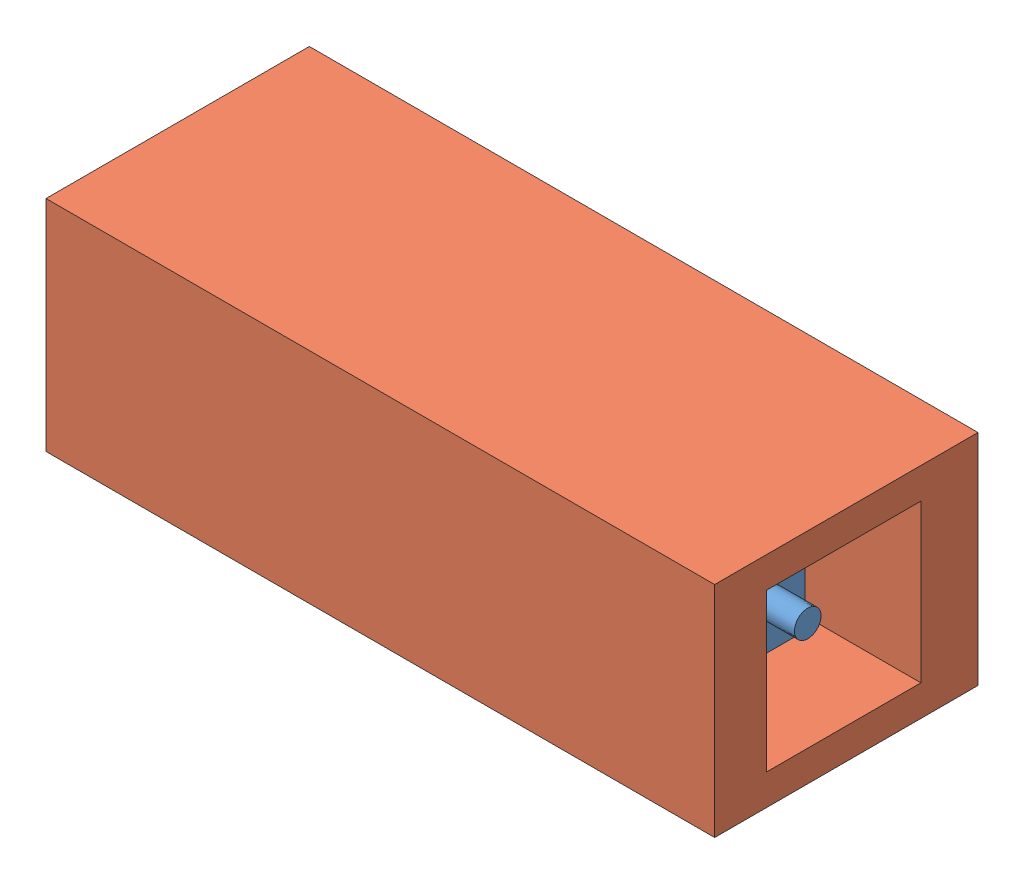
SolidWorks assembly v2, configuration Default. Lengths in mm.
Overall size (65 21.3 25.6).
3 component instances, 2 part files, 6 mates.
Components (placement in the parent):
- solenoid-1: solenoid [block] at (4.7939 41.8617 20.3007) size (30 15 15)
- solenoid-2: solenoid [stroke] at (-15.2061 41.8617 20.3007) x (1 0 0) z (0 0.379219 0.925307) size (57 6 6)
- Part3^v2-1: Part3^v2 [Default] at (4.7939 34.3617 20.3007) x (-1 0 0) z (0 -1 0) size (65 25.6 21.3) (virtual)
Mates (geometry in assembly coordinates):
- Concentric1: concentric aligned: cylinder of solenoid-1 through (4.7939 41.8617 20.3007) axis (-1 0 0) radius 3; cylinder of solenoid-2 through (-15.2061 41.8617 20.3007) axis (-1 0 0) radius 3
- LimitDistance2: limit distance = 20 mm aligned: plane of solenoid-2 through (-15.2061 41.8617 20.3007) normal (-1 0 0); plane of solenoid-1 through (4.7939 34.3617 27.0507) normal (-1 0 0)
- InPlace1: in place: plane of solenoid-1 through (4.7939 34.3617 26.3007) normal (0 -1 0); plane of ? through (0 34.3617 0) normal (0 -1 0); moOrthogonalPlaneRef_w of solenoid-1 through (4.7939 34.3617 26.3007) normal (0 -1 0); plane of ? through (0 34.3617 0) normal (0 0 -1); plane of solenoid-1 through (4.7939 34.3617 26.3007) normal (0 -1 0); plane of ? through (0 34.3617 0) normal (-1 0 0); plane of solenoid-1 through (4.7939 34.3617 27.0507) normal (0 -1 0); unknown of Part3^v2-1
- Coincident2: coincident aligned: plane of solenoid-1; plane of Part3^v2-1
- Coincident3: coincident aligned: moOrthogonalPlaneRef_w of solenoid-1 through (4.7939 34.3617 20.3007) normal (0 0 -1); plane of Part3^v2-1 through (4.7939 34.3617 20.3007) normal (0 0 -1)
- Coincident4: coincident anti-aligned: moOrthogonalPlaneRef_w of solenoid-1 through (4.7939 34.3617 20.3007) normal (1 0 0); plane of Part3^v2-1 through (4.7939 34.3617 20.3007) normal (-1 0 0)
